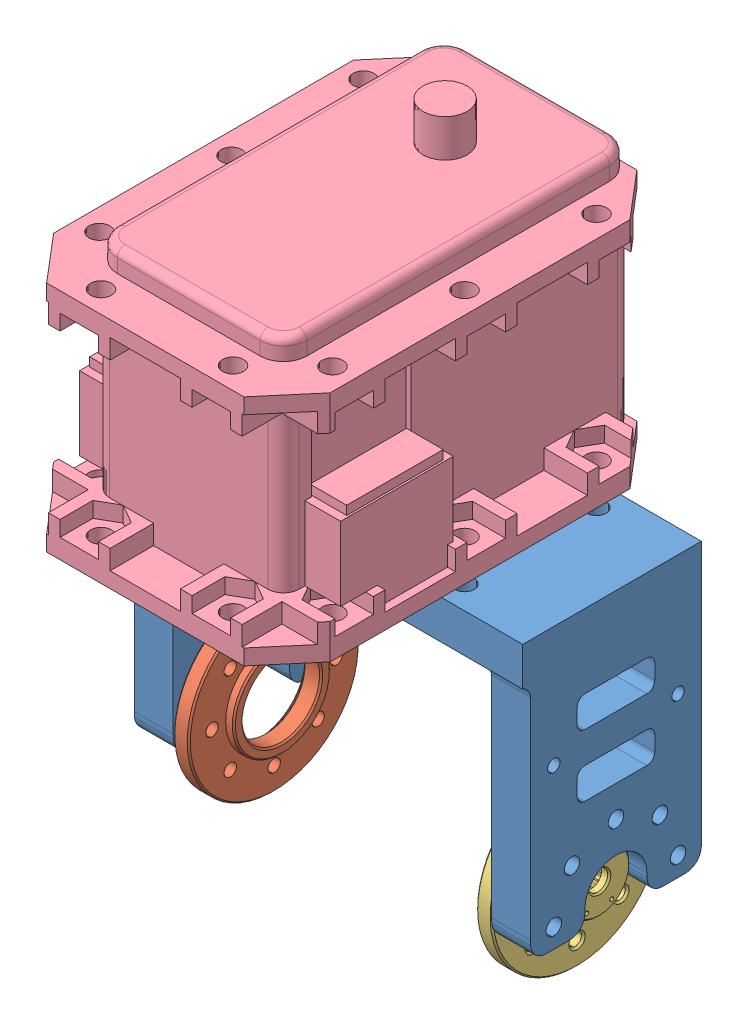
SolidWorks assembly Link7, configuration Default. Lengths in mm.
Overall size (51 84.85 50.71).
4 component instances, 4 part files, 9 mates.
Components (placement in the parent):
- myFR07-H101-1: myFR07-H101 [Default] at (-28.0061 50.3212 52.6334) size (51 36 23.13)
- HN07-i101-1: HN07-i101 [Default] at (-48.5061 21.8212 56.1334) x (0 1 0) z (0 0 1) size (22 3.05 22)
- HN07-N101-1: HN07-N101 [Default] at (-9.5061 21.8212 56.1334) x (0 0 -1) z (0 -1 0) size (22 5.85 22)
- MX-28T_R-1: MX-28T_R [Default] at (-28.0061 73.0712 52.6334) x (1 0 0) z (0 1 0) size (35.6 50.71 41.85)
Mates (geometry in assembly coordinates):
- Concentric1: concentric: circle of myFR07-H101-1; circle of MX-28T_R-1
- Concentric2: concentric: circle of myFR07-H101-1; circle of MX-28T_R-1
- Coincident1: coincident anti-aligned: plane of myFR07-H101-1 through (-28.0061 55.3212 52.6334) normal (0 1 0); plane of MX-28T_R-1 through (-28.0061 55.3212 52.6334) normal (0 -1 0)
- Concentric3: concentric: circle of myFR07-H101-1; circle of HN07-N101-1
- Concentric4: concentric: circle of myFR07-H101-1; circle of HN07-N101-1
- Coincident2: coincident anti-aligned: plane of myFR07-H101-1 through (-7.5061 21.8212 56.1334) normal (-1 0 0); plane of HN07-N101-1 through (-7.5061 21.8212 56.1334) normal (1 0 0)
- Concentric5: concentric: circle of myFR07-H101-1; circle of HN07-i101-1
- Concentric6: concentric: circle of myFR07-H101-1; circle of HN07-i101-1
- Coincident3: coincident anti-aligned: plane of myFR07-H101-1 through (-48.5061 21.8212 56.1334) normal (1 0 0); plane of HN07-i101-1 through (-48.5061 21.8212 56.1334) normal (-1 0 0)
